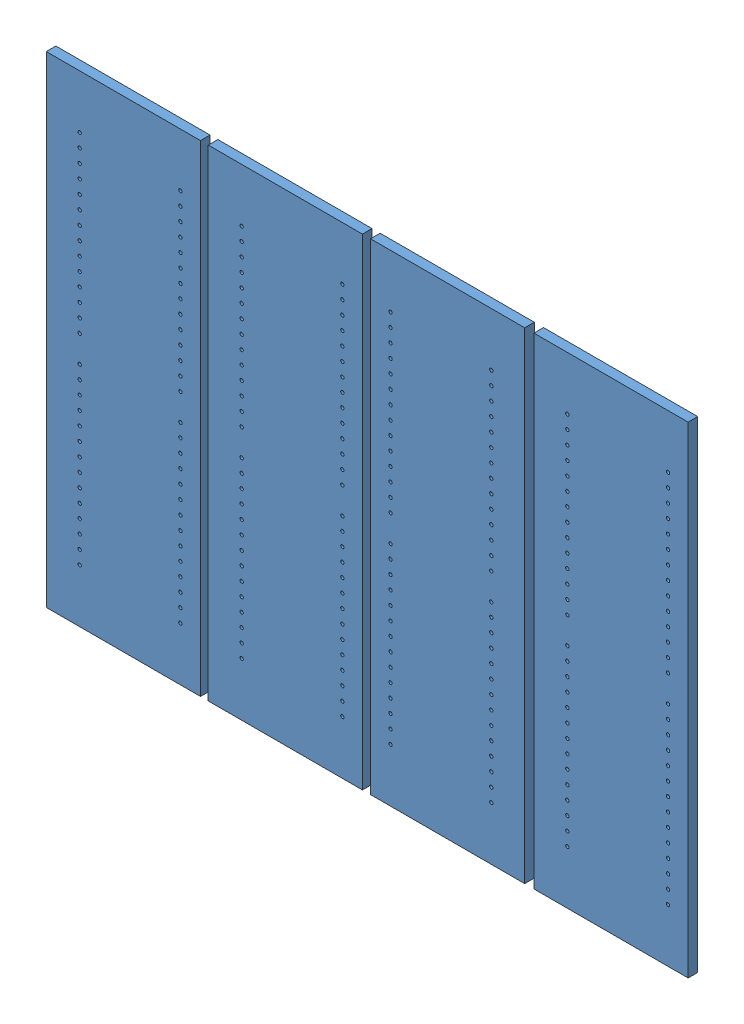
SolidWorks assembly Shelving_Uprights, configuration Default. Lengths in mm.
Overall size (1219.2 914.4 18.26).
4 component instances, 1 part files, 18 mates.
Components (placement in the parent):
- Hutch_Column-1: Hutch_Column [Default] at (3810.3531 457.2 0) x (0 0 1) z (-1 0 0) size (18.26 914.4 292.89)
- Hutch_Column-2: Hutch_Column [Default] at (3502.1157 457.2 0) x (0 0 1) z (1 0 0) size (18.26 914.4 292.89)
- Hutch_Column-3: Hutch_Column [Default] at (4120.7531 457.2 0) x (0 0 1) z (1 0 0) size (18.26 914.4 292.89)
- Hutch_Column-4: Hutch_Column [Default] at (3194.4469 457.2 0) x (0 0 1) z (1 0 0) size (18.26 914.4 292.89)
Mates (geometry in assembly coordinates):
- Coincident2: coincident anti-aligned: plane of Platform_Base-1 through (609.6 2133.6 0) normal (0 0 -1)
- Coincident19: coincident: point of Platform_Base-1
- Coincident24: coincident anti-aligned: plane of PartsCab_KeyboardDivider-1 through (2894.5743 2150.0782 0) normal (0 0 -1)
- Coincident27: coincident anti-aligned: plane of PartsCab_MidDivider-1 through (3903.1333 1315.4513 0) normal (0 0 -1)
- Coincident50: coincident anti-aligned: plane of Hutch_Column-4 through (3194.4469 457.2 0) normal (0 0 -1)
- Coincident51: coincident anti-aligned: plane of Hutch_Column-2 through (3502.1157 457.2 0) normal (0 0 -1)
- Coincident52: coincident anti-aligned: plane of Hutch_Column-1 through (3810.3531 457.2 0) normal (0 0 -1)
- Coincident53: coincident: line of assembly; line of Hutch_Column-3 through (3974.3063 0 0) axis (1 0 0); line of assembly
- Coincident54: coincident: line of assembly; line of Hutch_Column-3 through (914.4 4267.2 0) axis (0 0 1); line of assembly
- Coincident55: coincident: line of assembly; line of Hutch_Column-1 through (0 292.8938 3663.9062) axis (0 0 1); line of assembly
- Coincident56: coincident: line of assembly; line of Hutch_Column-4 through (292.8938 3048 0) axis (0 1 0); line of assembly
- Coincident57: coincident: line of assembly; line of Hutch_Column-2 through (292.8938 3355.6688 0) axis (0 1 0); line of assembly
- Coincident58: coincident: line of assembly; line of Hutch_Column-4 through (914.4 3048 914.4) axis (0 0 -1); line of assembly
- Coincident61: coincident anti-aligned: plane of Wing_BackPanel-2 through (5334 914.4 0) normal (0 0 -1)
- Coincident80: coincident anti-aligned: line of PartsCab_MidDivider-1 through (4267.2 1680.5763 0) axis (0 -1 0)
- Coincident81: coincident aligned: line of PartsCab_SideDivider-1 through (730.25 4267.2 1708.15) axis (0 0 1)
- Coincident82: coincident anti-aligned: line of PartsCab_SideDivider-1 through (609.6 4267.2 2438.4) axis (0 -1 0)
- Coincident83: coincident aligned: line of Wing_BackPanel-2 through (609.6 5791.2 609.6) axis (0 0 1)
